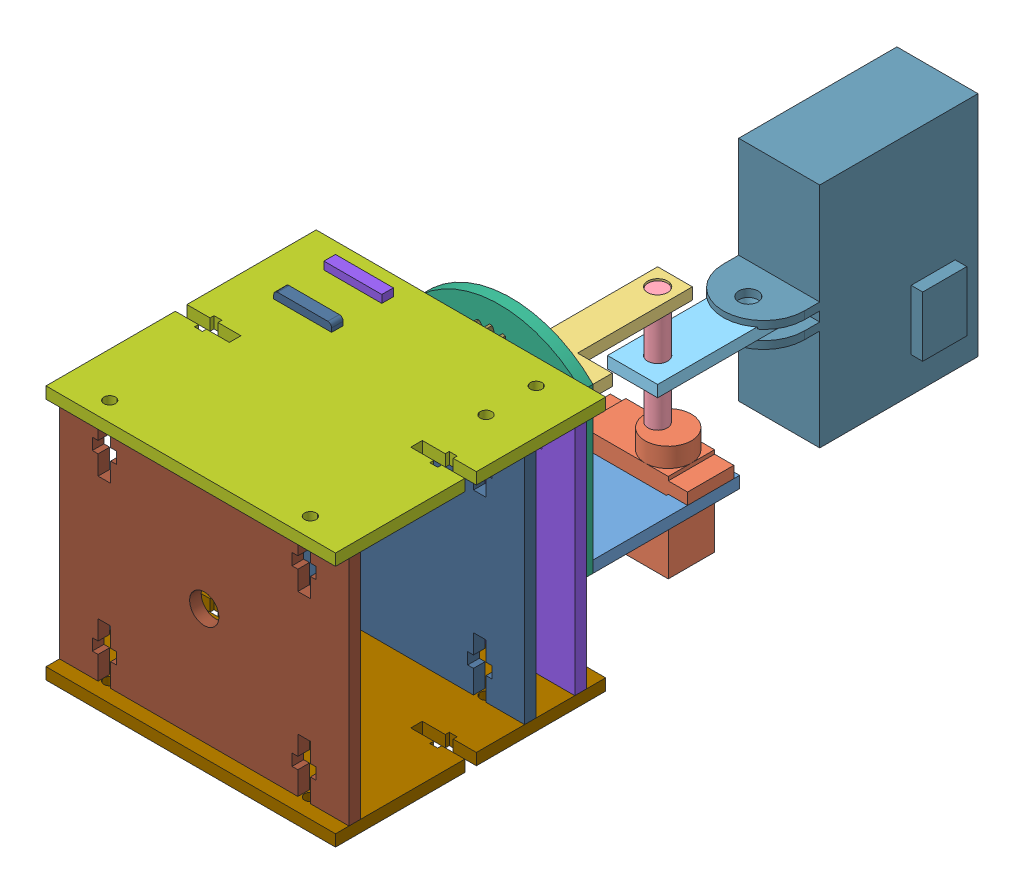
SolidWorks assembly Ensemble_tilt, configuration Défaut. Lengths in mm.
Overall size (80.42 80.9 185.75).
16 component instances, 14 part files, 26 mates.
Components (placement in the parent):
- Support_servo-1: Support_servo [Défaut] at (-2.9517 -2.2256 57) size (34.1 3 38)
- servo_tilt-1: servo_tilt [Défaut] at (-13.9017 -18.2256 32.5) size (32 28 12)
- tige_support_axe-1: tige_support_axe [Défaut] at (5.0983 37.2008 52) x (1 0 0) z (0 1 0) size (27 34.75 3)
- axe_tilt-1: axe_tilt [Défaut] at (0.5983 39.7744 26.75) x (1 0 0) z (0 -1 0) size (5 5 30)
- bielle-1: bielle [Défaut] at (7.0983 21.7891 15) x (0 0 -1) z (1 0 0) size (36.5 3 13)
- Plateautournant-1: Plateautournant [Default] at (-11.1633 11.1167 62.372) x (0.48128 -0.876567 0) z (0 0 1) size (60 58.8 18)
- Boitier-1: Boitier [Défaut] at (71.1575 218.9313 81.6997) x (1 0 0) z (0 -1 0) size (75 70 70)
  - cotebasemoteur-1: cotebasemoteur [Default] at (-90.9561 20.4636 166.9438) x (-1 0 0) z (0 0 1) size (75 70 3)
  - face_sup_sup_corr-2: face_sup_sup_corr [Défaut] at (-40.7724 -3.6997 229.9438) x (-1 0 0) z (0 -1 0) size (75 70 3)
  - cotebasepasmoteur-1: cotebasepasmoteur [Default] at (-65.5887 20.4636 232.9438) x (1 0 0) z (0 0 -1) size (75 70 3)
  - facesupbaseinf-3: facesupbaseinf [Default] at (-78.2724 9.3003 199.9438) x (0 0 -1) z (0 -1 0) size (65 75 3)
  - faceinfbase-1: faceinfbase [Default] at (-78.2724 54.8003 199.9438) x (0 0 -1) z (0 -1 0) size (60 75 3)
- servo_tilt-2: servo_tilt [Défaut] at (-22.8649 39.8876 94) x (1 0 0) z (0 1 0) size (32 28 12)
- rouemoteur-1: rouemoteur [Default] at (-6.8665 34.8214 56) size (22 22 3.5)
- axe_pan-1: axe_pan [Défaut] at (-7.1149 18.9876 75) size (8 8 30)
- gopro-1: gopro [Défaut] at (0.5983 23.0391 -4.75) x (0 -1 0) z (1 0 0) size (59 55.5 24)
Mates (geometry in assembly coordinates):
- Coïncidente1: coincident anti-aligned: plane of Support_servo-1 through (-2.9517 0.7744 57) normal (0 1 0); plane of servo_tilt-1 through (-13.9017 0.7744 32.5) normal (0 -1 0)
- Coïncidente3: coincident anti-aligned: plane of Support_servo-1 through (-2.9517 0.7744 20.5) normal (0 0 1); plane of servo_tilt-1 through (-13.9017 26.7166 20.5) normal (0 0 -1)
- Coïncidente4: coincident anti-aligned: plane of Support_servo-1 through (9.0983 0.7744 57) normal (-1 0 0); plane of servo_tilt-1 through (9.0983 26.7166 32.5) normal (1 0 0)
- Parallèle1: parallel anti-aligned: plane of Support_servo-1 through (-2.9517 0.7744 57) normal (0 1 0); plane of tige_support_axe-1 through (5.0983 37.2008 52) normal (0 -1 0)
- Coaxiale1: concentric anti-aligned: cylinder of tige_support_axe-1 through (0.5983 40.2008 26.75) axis (0 -1 0) radius 2.6; cylinder of axe_tilt-1 through (0.5983 9.7744 26.75) axis (0 1 0) radius 2.5
- Coïncidente6: coincident anti-aligned: plane of servo_tilt-1 through (-13.9017 9.7744 32.5) normal (0 1 0); plane of axe_tilt-1 through (0.5983 9.7744 26.75) normal (0 -1 0)
- Coïncidente7: coincident aligned: line of Support_servo-1 through (14.0983 0.7744 57) axis (0 -1 0); line of tige_support_axe-1 through (14.0983 40.2008 57) axis (0 -1 0)
- Coaxiale2: concentric anti-aligned: cylinder of axe_tilt-1 through (0.5983 9.7744 26.75) axis (0 1 0) radius 2.5; cylinder of bielle-1 through (0.5983 24.7891 26.75) axis (0 -1 0) radius 2.6
- Coïncidente8: coincident anti-aligned: plane of tige_support_axe-1 through (-12.9017 40.2008 57) normal (0 0 1); plane of Plateautournant-1 through (-7.1149 18.9876 57) normal (0 0 -1)
- Coïncidente10: coincident aligned: line of Support_servo-1 through (14.0983 0.7744 57) axis (0 -1 0); line of Plateautournant-1 through (14.0983 40.2008 57) axis (0 -1 0)
- Coïncidente26: coincident: point of tige_support_axe-1; point of Plateautournant-1
- Coïncidente16: coincident anti-aligned: plane of Plateautournant-1 through (-7.1149 18.9876 75) normal (0 0 1); plane of Boitier-1/face_sup_sup_corr-2 through (30.3851 -11.0124 75) normal (0 0 -1)
- Coaxiale4: concentric anti-aligned: circle of Plateautournant-1; circle of Boitier-1/face_sup_sup_corr-2
- Coïncidente17: coincident anti-aligned: plane of Boitier-1/face_sup_sup_corr-2 through (30.3851 -11.0124 75) normal (0 0 -1); plane of servo_tilt-2 through (-22.8649 39.8876 75) normal (0 0 1)
- Coïncidente18: coincident anti-aligned: plane of Boitier-1/face_sup_sup_corr-2 through (-22.8649 27.8876 75) normal (1 0 0); plane of servo_tilt-2 through (-22.8649 39.8876 49.0578) normal (-1 0 0)
- Coïncidente19: coincident anti-aligned: plane of Boitier-1/face_sup_sup_corr-2 through (-0.3649 27.8876 75) normal (0 1 0); plane of servo_tilt-2 through (-22.8649 27.8876 49.0578) normal (0 -1 0)
- Coïncidente20: coincident anti-aligned: plane of servo_tilt-2 through (-22.8649 39.8876 66) normal (0 0 -1); plane of rouemoteur-1 through (-6.8665 34.8214 66) normal (0 0 1)
- Coïncidente21: coincident anti-aligned: line of Plateautournant-1 through (-7.212 23.8268 70) axis (0 0 -1); line of rouemoteur-1 through (-7.212 23.8268 62.5) axis (0 0 1)
- Coïncidente22: coincident anti-aligned: plane of Plateautournant-1 through (-7.1149 18.9876 75) normal (0 0 1); plane of axe_pan-1 through (-7.1149 18.9876 75) normal (0 0 -1)
- Coaxiale5: concentric anti-aligned: circle of Boitier-1/face_sup_sup_corr-2; circle of axe_pan-1
- Coïncidente23: coincident anti-aligned: plane of bielle-1 through (-5.9017 21.7891 38.5) normal (0 -1 0); plane of gopro-1 through (0.5983 21.7891 58.25) normal (0 1 0)
- Coaxiale6: concentric anti-aligned: circle of bielle-1; circle of gopro-1
- Angle1: planar angle = 4.712389 rad aligned: line of bielle-1 through (-5.9017 21.7891 -3.25) axis (0 0 1); line of servo_tilt-1 through (9.0983 -18.2256 20.5) axis (-1 0 0)
- Angle2: planar angle = 0 rad aligned: plane of gopro-1 through (-9.9017 24.2891 -0.75) normal (-1 0 0); plane of bielle-1 through (-5.9017 24.7891 15) normal (-1 0 0)
- Coïncidente27: coincident: point of Support_servo-1; point of Plateautournant-1
- Distance4: distance = 12.0147 mm anti-aligned: plane of servo_tilt-1 through (-13.9017 9.7744 32.5) normal (0 1 0); plane of bielle-1 through (7.0983 21.7891 15) normal (0 -1 0)
